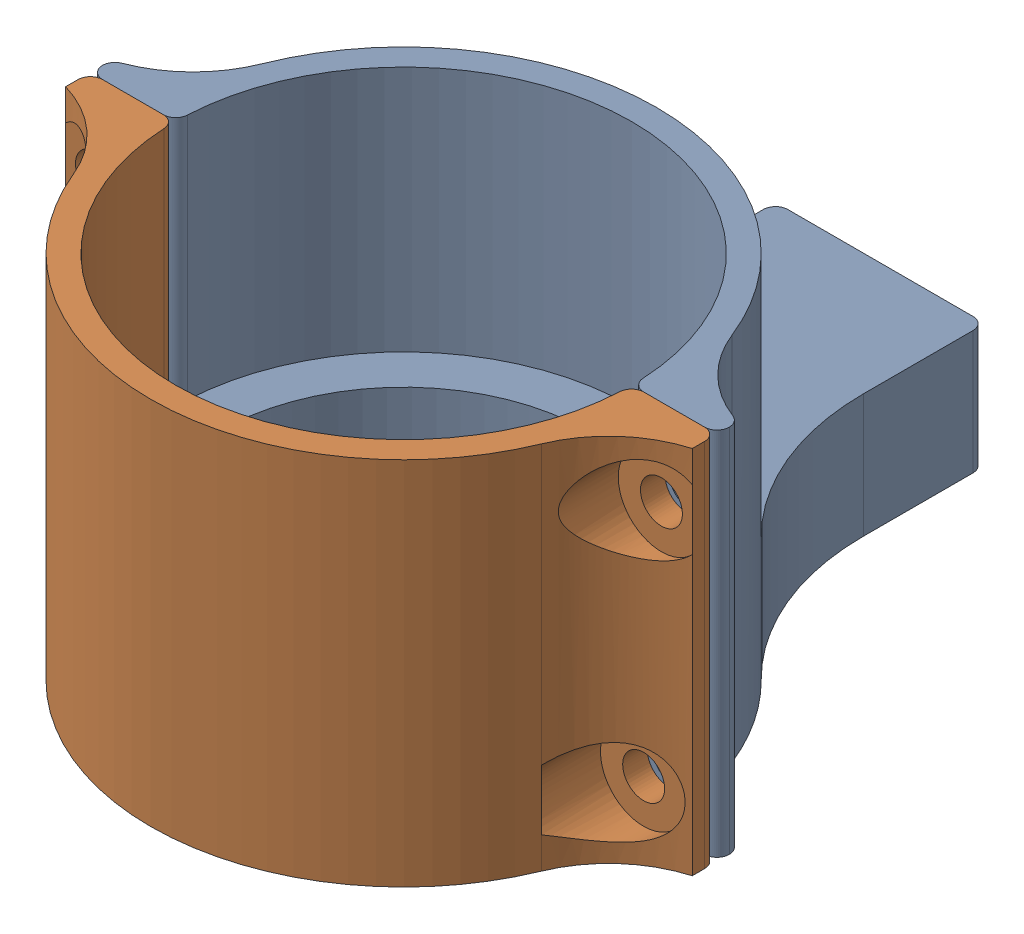
SolidWorks assembly asm_support_reglable, configuration Défaut. Lengths in mm.
Overall size (51.5 30 59.15).
2 component instances, 2 part files, 3 mates.
Components (placement in the parent):
- support_2_parties-1: support_2_parties [Défaut] at origin size (50.8 30 38.65)
- support_1_parties-1: support_1_parties [Défaut] at (0 5 59.1548) x (-1 0 0) z (0 0 -1) size (51.5 30 20.5)
Mates (geometry in assembly coordinates):
- Coïncidente1: coincident aligned: plane of support_2_parties-1 through (0 5 38.6548) normal (0 1 0); plane of support_1_parties-1 through (0 5 38.6548) normal (0 1 0)
- Coïncidente2: coincident anti-aligned: plane of support_2_parties-1 through (18.5 25 38.6548) normal (0 0 1); plane of support_1_parties-1 through (25.4022 25 38.6548) normal (0 0 -1)
- Coaxiale1: concentric aligned: cylinder of support_2_parties-1 through (0 25 38.6548) axis (0 -1 0) radius 18.5; cylinder of support_1_parties-1 through (0 25 38.6548) axis (0 -1 0) radius 18.5
